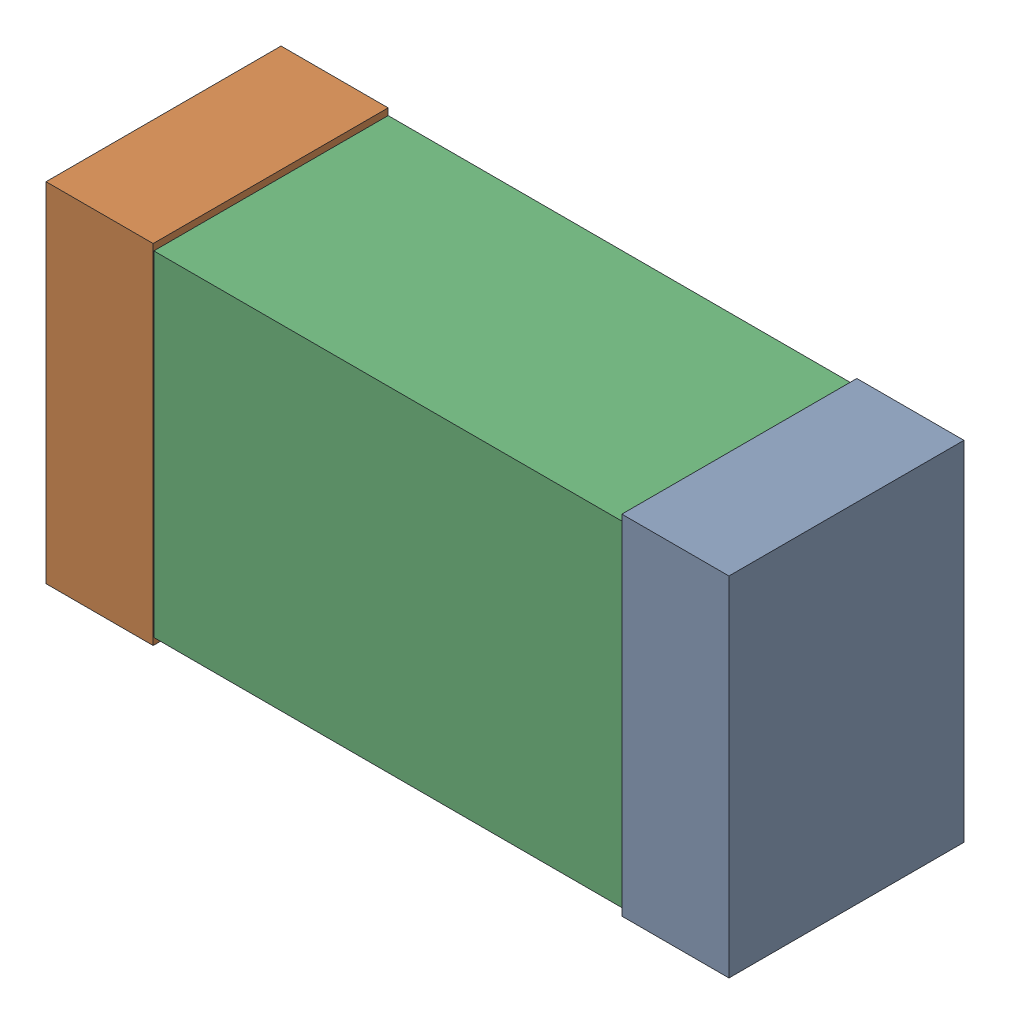
SolidWorks assembly R5, configuration Default. Lengths in mm.
Overall size (1.02 0.52 0.35).
6 component instances, 2 part files, 0 mates.
Components (placement in the parent):
- 870940480-1: 870940480 [Default] at (60.8558 27.4552 0) size (0.16 0.52 0.35)
  - Extruded-1: Extruded [Default] at origin size (0.16 0.52 0.35)
- 870940480-2: 870940480 [Default] at (59.9958 27.4552 0) size (0.16 0.52 0.35)
  - Extruded-1: Extruded [Default] at origin size (0.16 0.52 0.35)
- 870940640-1: 870940640 [Default] at (60.4258 27.4552 0) size (1 0.5 0.35)
  - Extruded_2-1: Extruded_2 [Default] at origin size (1 0.5 0.35)
